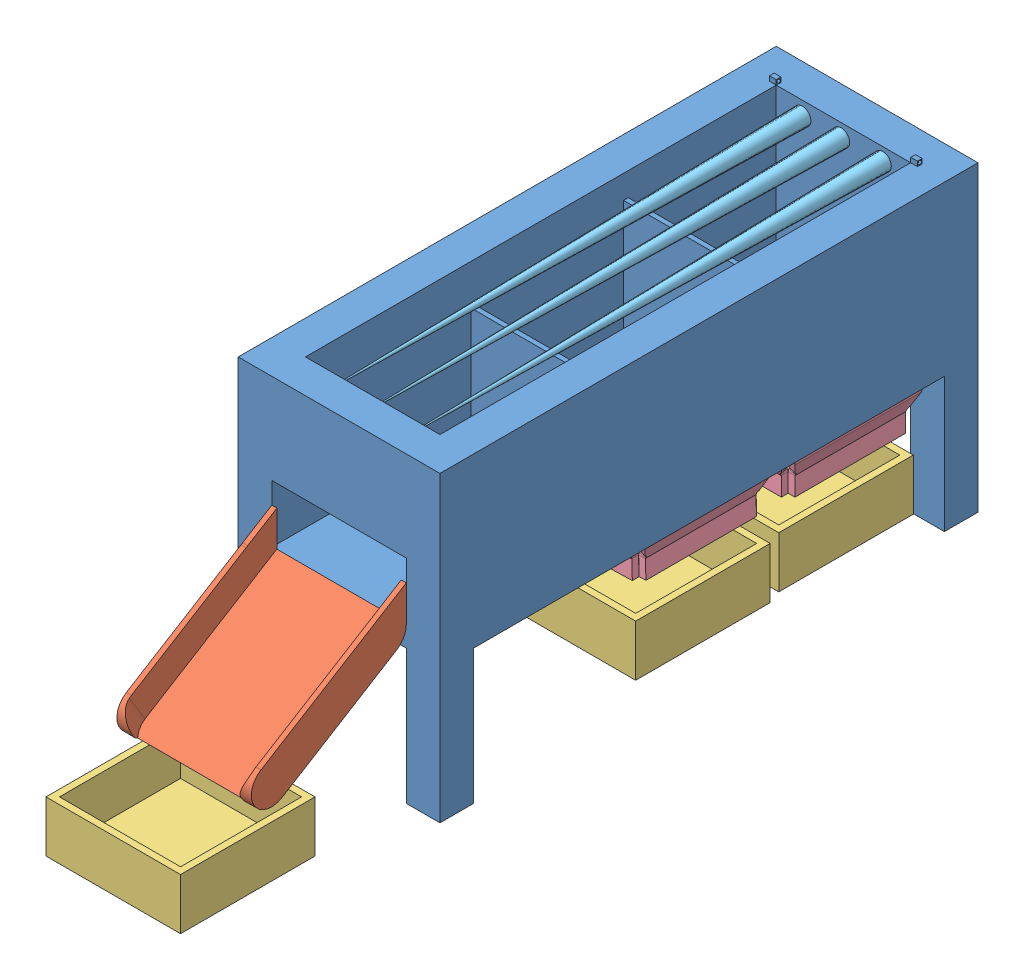
SolidWorks assembly AssemSortingBesarTomat, configuration Default. Lengths in mm.
Overall size (300 457.28 1135.45).
10 component instances, 5 part files, 7 mates.
Components (placement in the parent):
- alat sortir buah-1: alat sortir buah [Default] at (389.0112 482.3798 510.4176) x (0 0 1) z (0 -1 0) size (800 300 457)
- Part2-1: Part2 [Default] at (507.6916 412.7556 993.4603) x (-0.000435 0.292039 0.956406) z (-1 0 -0.000455) size (192.29 240.11 200)
- kotak penampungan-1: kotak penampungan [Default] at (507.3661 182.175 1298.8151) x (1 0 0) z (0 1 0) size (200 200 76.2)
- corong_lagi-1: corong_lagi [Default] at (517.7053 352.3798 215.6639) size (220 87.19 210)
- corong_lagi-2: corong_lagi [Default] at (518.497 358.5708 439.7099) x (0.999567 0.029419 0) z (0 0 1) size (220 87.19 210)
- kotak penampungan-2: kotak penampungan [Default] at (520.4536 183.2154 635.1413) x (1 0 0) z (0 1 0) size (200 200 76.2)
- kotak penampungan-3: kotak penampungan [Default] at (511.9065 182.1014 413.8036) x (1 0 0) z (0 1 0) size (200 200 76.2)
- besi untuk sortir-1: besi untuk sortir [Default] at (466.1545 613.4831 213.3693) size (25.4 25.4 700)
- besi untuk sortir-2: besi untuk sortir [Default] at (404.205 612.9596 213.3693) x (0.999898 0.014298 0) z (0 0 1) size (25.4 25.4 700)
- besi untuk sortir-3: besi untuk sortir [Default] at (346.5912 611.9861 213.3693) x (0.949732 -0.313063 0) z (0 0 1) size (25.4 25.4 700)
Mates (geometry in assembly coordinates):
- Coincident16: coincident anti-aligned: line of alat sortir buah-1 through (307.7053 498.3343 963.3693) axis (0 -1 0); line of Part2-1 through (307.7053 412.7556 963.3693) axis (0 1 0)
- Coincident18: coincident anti-aligned: line of alat sortir buah-1 through (307.7053 382.3798 413.3693) axis (0 0 -1); line of corong_lagi-1 through (307.7053 382.3798 216.4005) axis (0 0 1)
- Coincident20: coincident anti-aligned: line of alat sortir buah-1 through (307.7053 382.3798 640.3693) axis (0 0 -1); line of corong_lagi-2 through (307.7053 382.3798 440.4465) axis (0 0 1)
- Coincident22: coincident anti-aligned: plane of alat sortir buah-1 through (307.7053 632.3798 213.3693) normal (0 0 1); plane of besi untuk sortir-1 through (466.1545 613.4831 213.3693) normal (0 0 -1)
- Coincident23: coincident aligned: plane of alat sortir buah-1 through (307.7053 632.3798 213.3693) normal (0 0 1); circle of besi untuk sortir-3
- Coincident24: coincident aligned: plane of alat sortir buah-1 through (307.7053 632.3798 213.3693) normal (0 0 1); circle of besi untuk sortir-2
- Coincident25: coincident aligned: plane of alat sortir buah-1 through (307.7053 632.3798 213.3693) normal (0 0 1); circle of besi untuk sortir-2
